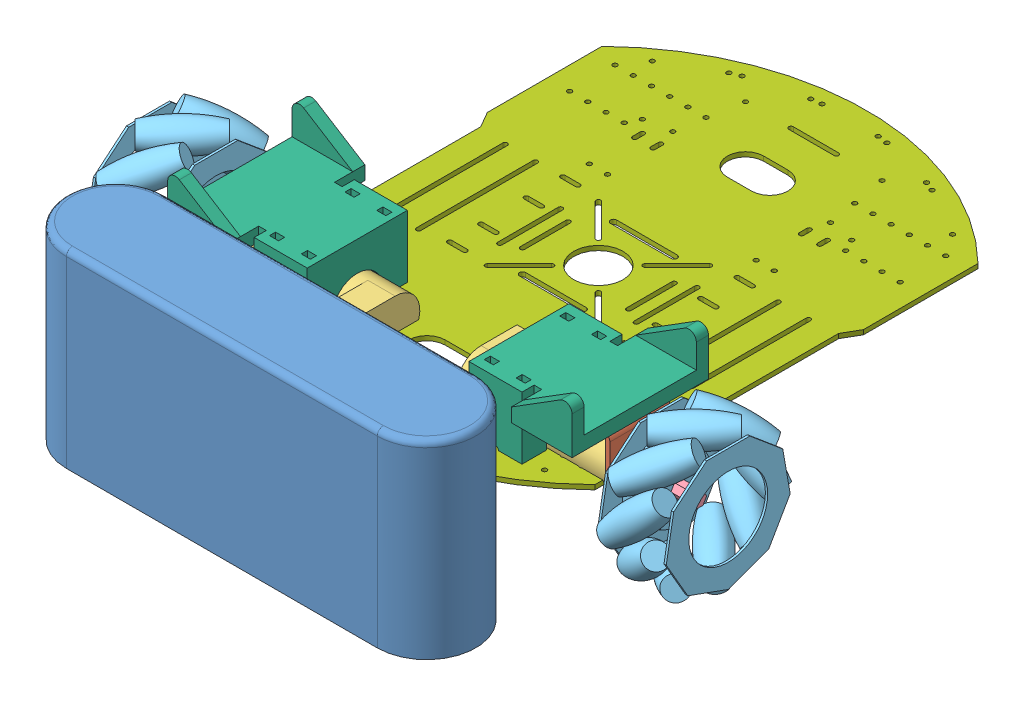
SolidWorks assembly scene1, configuration Default. Lengths in mm.
Overall size (382.6 125.31 440.62).
14 component instances, 7 part files, 4 mates.
Components (placement in the parent):
- docking station-1: docking station [Default] at origin size (270 125 112)
- motor base assy-1: motor base assy [Default] at (130.3012 48 -110.1164) size (163 105.51 96.18)
  - motor_bracket-1: motor_bracket [Default] at origin size (42.8 47.2 40)
  - motor-1: motor [Default] at (-84 0 0) x (1 0 0) z (0 1 0) size (122 56 32.5)
  - wheel_adapter-1: wheel_adapter [Default] at (20 0 0) x (1 0 0) z (0 -0.866025 0.5) size (33 10 10)
  - wheel-1: wheel [Default] at (38.5 0 0) x (0 0 -1) z (1 0 0) size (96.18 96.31 45)
  - Part4^motor base assy-1: Part4^motor base assy [Default] at (0 27.2 0) x (1 0 0) z (0 1 0) size (80 90 67.2) (virtual)
- motor base assy-2: motor base assy [Default] at (-130.3012 48 -110.1164) x (-1 0 0) z (0 0 -1) size (163 105.51 96.18)
  - motor_bracket-1: motor_bracket [Default] at origin size (42.8 47.2 40)
  - motor-1: motor [Default] at (-84 0 0) x (1 0 0) z (0 1 0) size (122 56 32.5)
  - wheel_adapter-1: wheel_adapter [Default] at (20 0 0) x (1 0 0) z (0 -0.866025 0.5) size (33 10 10)
  - wheel-1: wheel [Default] at (38.5 0 0) x (0 0 -1) z (1 0 0) size (96.18 96.31 45)
  - Part4^motor base assy-1: Part4^motor base assy [Default] at (0 27.2 0) x (1 0 0) z (0 1 0) size (80 90 67.2) (virtual)
- moebius_base_extended-1: moebius_base_extended [Default] at (0 40 -215.8) size (248 3 354)
Mates (geometry in assembly coordinates):
- Coincident5: coincident aligned: plane of motor base assy-1/wheel-1 through (168.8012 0 -110.1164) normal (0 1 0)
- Distance1: distance = 40 mm anti-aligned: plane of moebius_base_extended-1 through (0 40 -215.8) normal (0 -1 0)
- Tangent1: tangent: plane of docking station-1 through (-102.5 125 -38.8) normal (0 0 -1); circle of moebius_base_extended-1
- Coincident8: coincident aligned: plane of moebius_base_extended-1 through (0 40 -215.8) normal (1 0 0)
